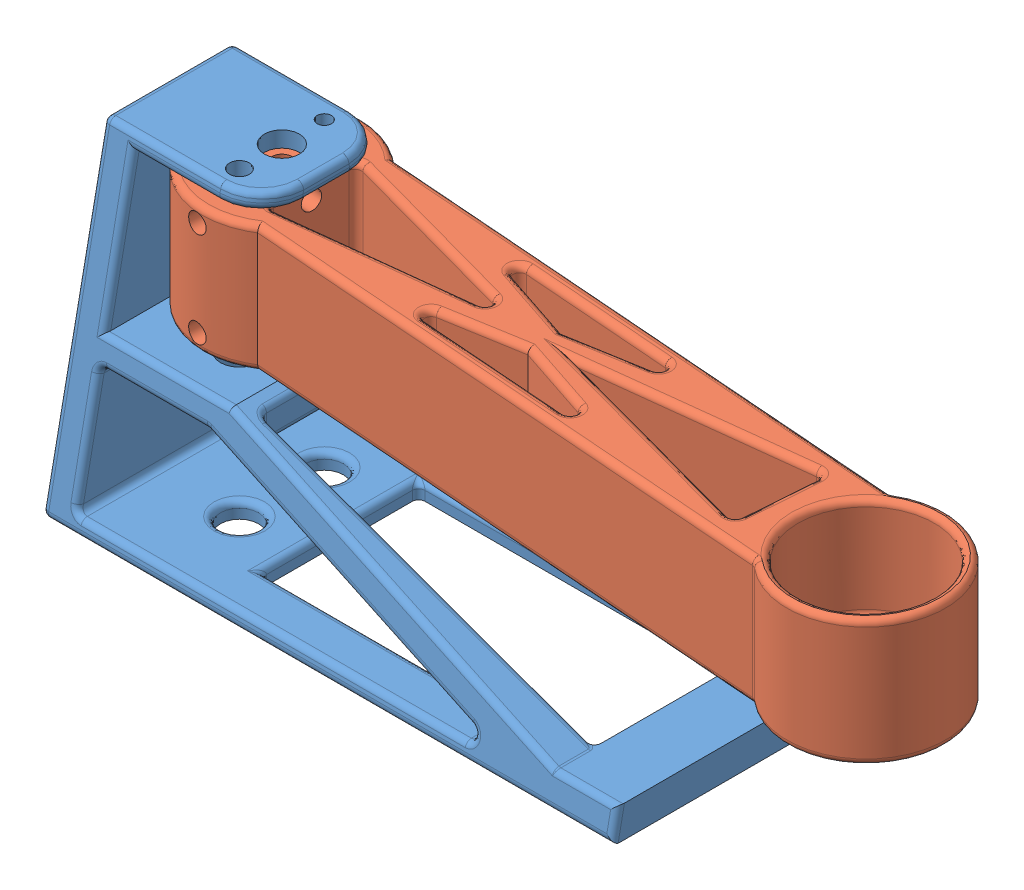
SolidWorks assembly Assem1, configuration Default. Lengths in mm.
Overall size (166.53 63.5 51.77).
2 component instances, 2 part files, 2 mates.
Components (placement in the parent):
- PID_mount_RBE_2001-1: PID_mount_RBE_2001 [Default] at (-116.1555 -10.3966 -8.7707) size (114.3 63.5 50.24)
- PID_Link_RBE_2001-1: PID_Link_RBE_2001 [Default] at (-106.9208 24.5284 28.331) x (0.997128 0 0.07573) z (-0.07573 0 0.997128) size (158.75 25.63 31.75)
Mates (geometry in assembly coordinates):
- Concentric1: concentric aligned: cylinder of PID_mount_RBE_2001-1 through (-93.2955 46.7534 16.6293) axis (0 1 0) radius 3.5; circle of PID_Link_RBE_2001-1
- Coincident1: coincident anti-aligned: plane of PID_mount_RBE_2001-1 through (-109.8055 49.9284 38.728) normal (0 -1 0); plane of PID_Link_RBE_2001-1 through (-106.9208 49.9284 28.331) normal (0 1 0)
